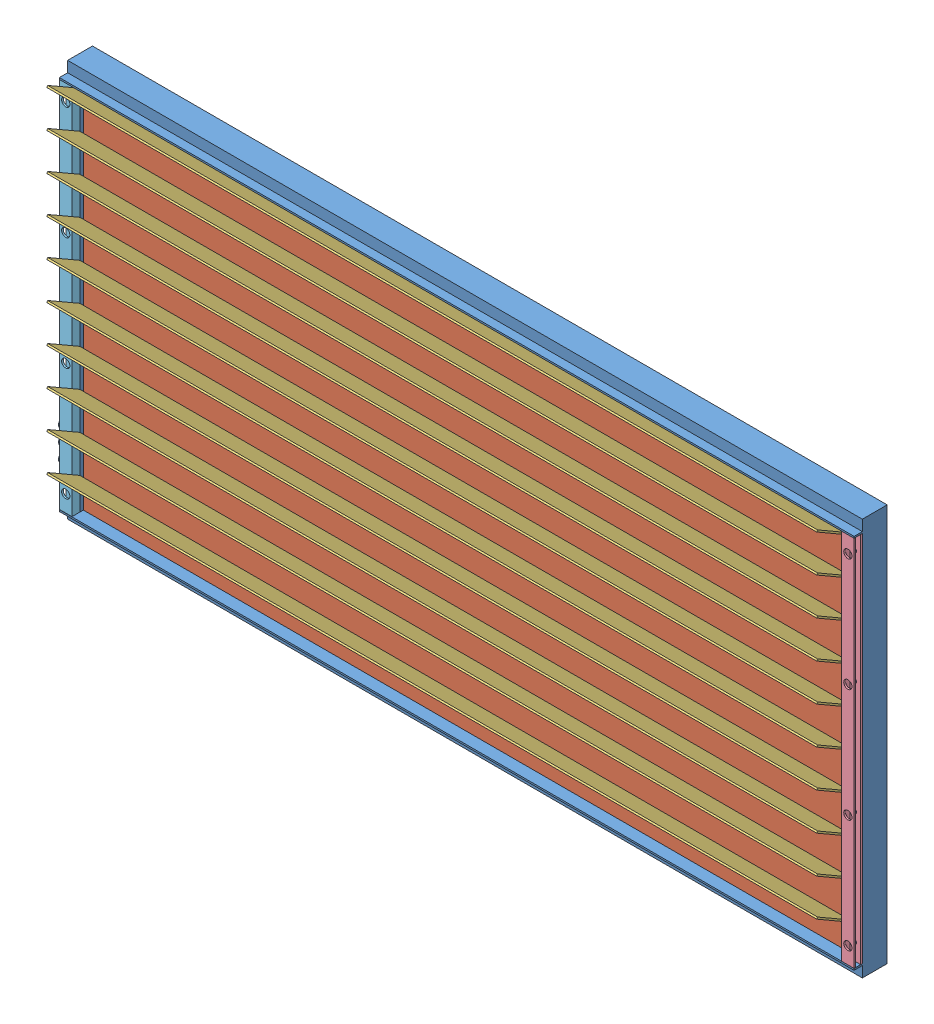
SolidWorks assembly Window, configuration Default. Lengths in mm.
Overall size (1244.6 610.7 89.08).
16 component instances, 5 part files, 9 mates.
Components (placement in the parent):
- Frame-1: Frame [Default] at (181.0304 593.5363 1109.4762) size (1244.6 609.6 50.8)
- Glass-1: Glass [Default] at (181.0304 593.5363 1099.9512) size (1206.5 596.9 6.35)
- Glass-2: Glass [Default] at (181.0304 593.5363 1119.0012) size (1206.5 596.9 6.35)
- Radiation Covering-1: Radiation Covering [Default] at (699.1566 300.73 1605.8717) x (-1 0 0) z (0 0 -1) size (1219.2 591.65 51.27) (flexible)
  - Strip-1: Strip [Default] at (518.1262 583.3188 451.7481) x (1 0 0) z (0 -0.866025 -0.5) size (1206.5 57.15 2.54)
  - Holding Bar-3: Holding Bar [Default] at (-72.4238 292.8063 470.9955) size (19.05 571.5 12.7)
  - Holding Bar Right-1: Holding Bar Right [Default] at (1108.6762 292.8063 471.2819) size (19.05 571.5 12.7)
  - Strip-2: Strip [Default] at (518.1262 526.1688 451.7481) x (1 0 0) z (0 -0.866025 -0.5) size (1206.5 57.15 2.54)
  - Strip-3: Strip [Default] at (518.1262 469.0188 451.7481) x (1 0 0) z (0 -0.866025 -0.5) size (1206.5 57.15 2.54)
  - Strip-4: Strip [Default] at (518.1262 411.8688 451.7481) x (1 0 0) z (0 -0.866025 -0.5) size (1206.5 57.15 2.54)
  - Strip-5: Strip [Default] at (518.1262 354.7188 451.7481) x (1 0 0) z (0 -0.866025 -0.5) size (1206.5 57.15 2.54)
  - Strip-6: Strip [Default] at (518.1262 297.5688 451.7481) x (1 0 0) z (0 -0.866025 -0.5) size (1206.5 57.15 2.54)
  - Strip-7: Strip [Default] at (518.1262 240.4188 451.7481) x (1 0 0) z (0 -0.866025 -0.5) size (1206.5 57.15 2.54)
  - Strip-8: Strip [Default] at (518.1262 183.2688 451.7481) x (1 0 0) z (0 -0.866025 -0.5) size (1206.5 57.15 2.54)
  - Strip-9: Strip [Default] at (518.1262 126.1188 451.7481) x (1 0 0) z (0 -0.866025 -0.5) size (1206.5 57.15 2.54)
  - Strip-10: Strip [Default] at (518.1262 68.9688 451.7481) x (1 0 0) z (0 -0.866025 -0.5) size (1206.5 57.15 2.54)
Mates (geometry in assembly coordinates):
- Coincident1: coincident anti-aligned: plane of Frame-1 through (790.6304 891.9863 1117.0962) normal (0 -1 0); plane of Glass-2 through (784.2804 891.9863 1117.0962) normal (0 1 0)
- Coincident2: coincident anti-aligned: plane of Frame-1 through (784.2804 288.7363 1117.0962) normal (-1 0 0); plane of Glass-2 through (784.2804 593.5363 1119.0012) normal (1 0 0)
- Coincident4: coincident anti-aligned: plane of Frame-1 through (-420.9496 898.3363 1122.1762) normal (0 0 -1); plane of Glass-2 through (784.2804 890.7163 1122.1762) normal (0 0 1)
- Coincident5: coincident anti-aligned: plane of Frame-1 through (-422.2196 898.3363 1098.0462) normal (1 0 0); plane of Glass-1 through (-422.2196 593.5363 1099.9512) normal (-1 0 0)
- Coincident6: coincident anti-aligned: plane of Frame-1 through (790.6304 891.9863 1098.0462) normal (0 -1 0); plane of Glass-1 through (784.2804 891.9863 1098.0462) normal (0 1 0)
- Coincident7: coincident anti-aligned: plane of Frame-1 through (-420.9496 898.3363 1103.1262) normal (0 0 -1); plane of Glass-1 through (784.2804 890.7163 1103.1262) normal (0 0 1)
- Coincident8: coincident anti-aligned: plane of Frame-1 through (-409.5196 898.3363 1128.5262) normal (0 0 1); plane of Radiation Covering-1/Holding Bar-3 through (771.5804 879.2863 1128.5262) normal (0 0 -1)
- Coincident9: coincident anti-aligned: plane of Frame-1 through (790.6304 879.2863 1123.4462) normal (0 -1 0); plane of Radiation Covering-1/Holding Bar-3 through (771.5804 879.2863 1134.8762) normal (0 1 0)
- Coincident10: coincident aligned: plane of Frame-1 through (771.5804 288.7363 1123.4462) normal (-1 0 0); plane of Radiation Covering-1/Holding Bar-3 through (771.5804 879.2863 1128.5262) normal (-1 0 0)
